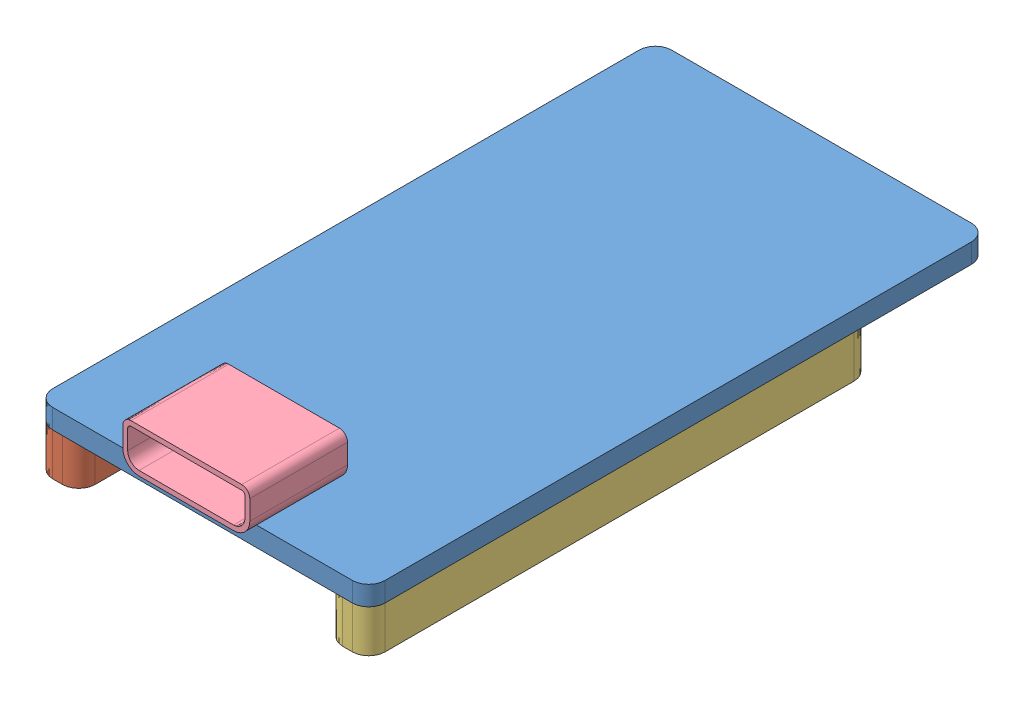
SolidWorks assembly redbear_duo_assy, configuration Default. Lengths in mm.
Overall size (20.4 6.5 39).
4 component instances, 4 part files, 0 mates.
Components (placement in the parent):
- Component1-1: Component1 [Default] at (19.197 -0.736 15.8953) size (20.4 1.2 38)
- Component2-1: Component2 [Default] at (19.197 3.264 15.8953) size (2.6 2.6 30.8)
- Component3-1: Component3 [Default] at (19.197 -0.736 15.8953) size (2.6 2.6 30.8)
- Component4-1: Component4 [Default] at (19.197 -0.736 15.1953) size (7.8 2.7 6)
